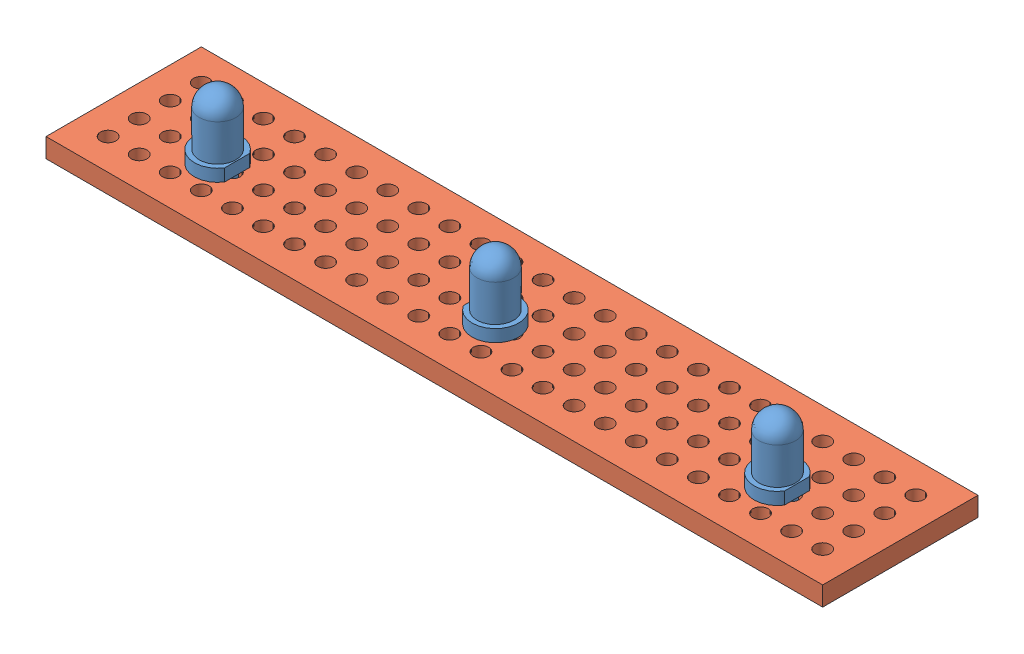
SolidWorks assembly PCB, STATUS LED, TOP ASSY, configuration Default. Lengths in mm.
Overall size (63.5 8.5 12.7).
4 component instances, 2 part files, 10 mates.
Components (placement in the parent):
- LED DIP 3mm-1: LED DIP 3mm [Blue] at (-22.8283 -0.2126 1.241) x (0 0 1) z (0 1 0) size (3.8 3.5 8.5)
- LED DIP 3mm-2: LED DIP 3mm [Red] at (-0.117 -0.2126 1.241) x (0 0 -1) z (0 1 0) size (3.8 3.5 8.5)
- LED DIP 3mm-3: LED DIP 3mm [Green] at (22.9363 -0.2126 1.241) x (0 0 1) z (0 1 0) size (3.8 3.5 8.5)
- Breadboard 2'5x0'5-1: Breadboard 2'5x0'5 [Default] x (-1 0 0) z (0 0 -1) size (63.5 1.6 12.7)
Mates (geometry in assembly coordinates):
- Coincident2494: coincident anti-aligned: plane of LED DIP 3mm-1 through (-22.8283 0.7874 1.241) normal (0 -1 0); plane of Breadboard 2'5x0'5-1 through (-31.75 0.7874 6.35) normal (0 1 0)
- Coincident2497: coincident aligned: plane of LED DIP 3mm-1 through (-22.8283 -4.3854 1.016) normal (0 0 -1); plane of LED DIP 3mm-2 through (-0.117 -4.3854 1.016) normal (0 0 -1)
- Distance1: distance = 7.366 mm aligned: plane of Breadboard 2'5x0'5-1 through (31.75 0.7874 -6.35) normal (0 0 -1); plane of LED DIP 3mm-1 through (-22.8283 -4.3854 1.016) normal (0 0 -1)
- Coincident2495: coincident anti-aligned: plane of LED DIP 3mm-2 through (-0.117 0.7874 1.241) normal (0 -1 0); plane of Breadboard 2'5x0'5-1 through (-31.75 0.7874 6.35) normal (0 1 0)
- Coincident2498: coincident aligned: plane of LED DIP 3mm-2 through (-0.117 -4.3854 1.016) normal (0 0 -1); plane of LED DIP 3mm-3 through (22.9363 -4.3854 1.016) normal (0 0 -1)
- Coincident2496: coincident anti-aligned: plane of LED DIP 3mm-3 through (22.9363 0.7874 1.241) normal (0 -1 0); plane of Breadboard 2'5x0'5-1 through (-31.75 0.7874 6.35) normal (0 1 0)
- Parallel9: parallel aligned: plane of LED DIP 3mm-3 through (22.9363 -4.3854 1.016) normal (0 0 -1); plane of Breadboard 2'5x0'5-1 through (31.75 0.7874 -6.35) normal (0 0 -1)
- Coincident2504: coincident aligned: plane of Breadboard 2'5x0'5-1; plane of assembly through (0 0 0) normal (0 1 0)
- Coincident2505: coincident anti-aligned: plane of Breadboard 2'5x0'5-1 through (0 0 0) normal (-1 0 0); plane of assembly through (0 0 0) normal (1 0 0)
- Coincident2506: coincident anti-aligned: plane of Breadboard 2'5x0'5-1 through (0 0 0) normal (0 0 -1); plane of assembly through (0 0 0) normal (0 0 1)
